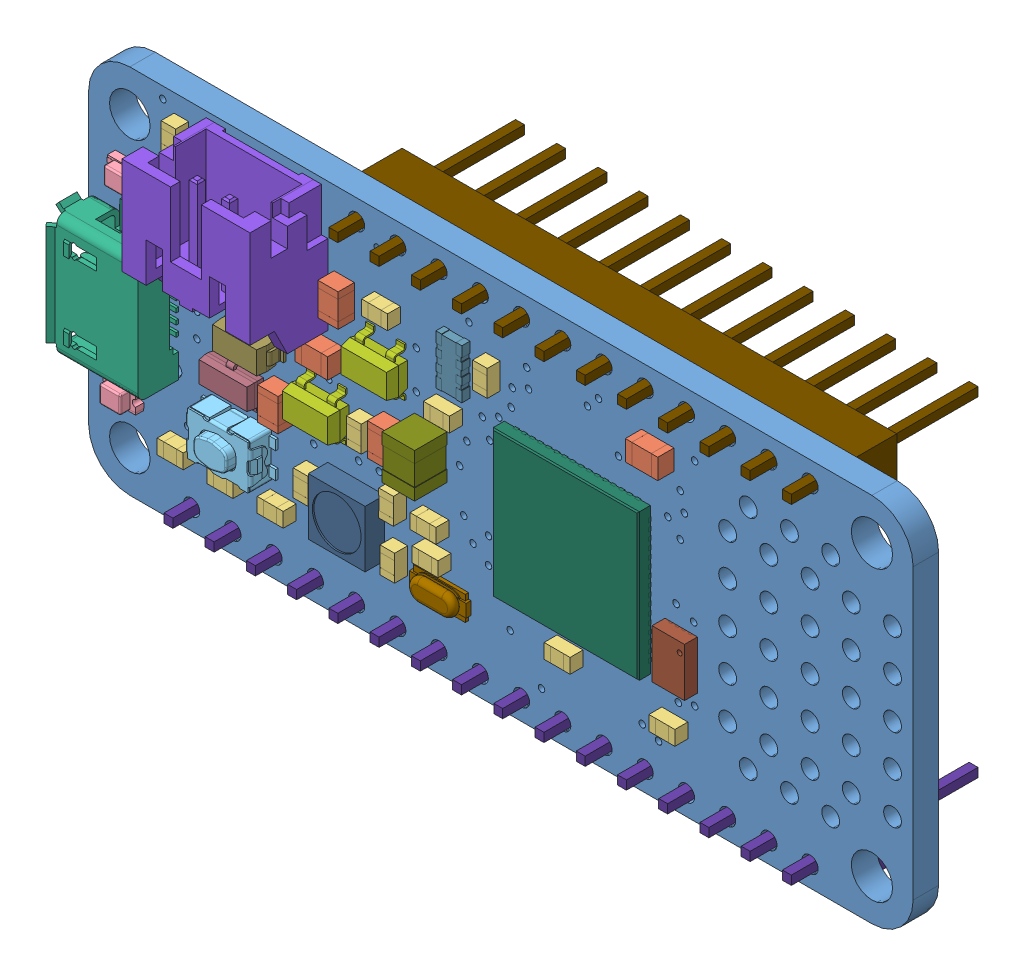
SolidWorks assembly 3857 Adafruit Feather M4 Express headers, configuration Default. Lengths in mm.
Overall size (50.85 22.86 14.87).
41 component instances, 18 part files, 6 mates.
Components (placement in the parent):
- 3857 Adafruit Feather M4 Express-1: 3857 Adafruit Feather M4 Express [Default] at origin size (50.85 22.86 6.37)
  - 3857 Adafruit Feather M4 Express(2)^3857 Adafruit Feather M4 Express-1: 3857 Adafruit Feather M4 Express(2)^3857 Adafruit Feather M4 Express [Default] at origin size (50.85 22.86 6.37) (virtual)
    - PCB Component^3857 Adafruit Feather M4 Express(2)_3857 Adafruit Feather M4 Express-1: PCB Component^3857 Adafruit Feather M4 Express(2)_3857 Adafruit Feather M4 Express [Default] at origin size (50.85 22.86 6.37) (virtual)
      - Board^PCB Component_3857 Adafruit Feather M4 Express(2)_3857 Adafruit Feather M4 Express-1: Board^PCB Component_3857 Adafruit Feather M4 Express(2)_3857 Adafruit Feather M4 Express [Default] at origin size (50.8 22.86 1.57) (virtual)
      - 10uF^PCB Component_3857 Adafruit Feather M4 Express(2)_3857 Adafruit Feather M4 Express-1: 10uF^PCB Component_3857 Adafruit Feather M4 Express(2)_3857 Adafruit Feather M4 Express [Default] at (12.042 9.838 1.57) x (0 -1 0) z (0 0 1) size (2 1.25 1) (virtual)
      - 10uF^PCB Component_3857 Adafruit Feather M4 Express(2)_3857 Adafruit Feather M4 Express-2: 10uF^PCB Component_3857 Adafruit Feather M4 Express(2)_3857 Adafruit Feather M4 Express [Default] at (14.728 13.858 1.57) size (2 1.25 1) (virtual)
      - 10uF^PCB Component_3857 Adafruit Feather M4 Express(2)_3857 Adafruit Feather M4 Express-3: 10uF^PCB Component_3857 Adafruit Feather M4 Express(2)_3857 Adafruit Feather M4 Express [Default] at (15.748 17.272 1.57) x (0 -1 0) z (0 0 1) size (2 1.25 1) (virtual)
      - 10uF^PCB Component_3857 Adafruit Feather M4 Express(2)_3857 Adafruit Feather M4 Express-4: 10uF^PCB Component_3857 Adafruit Feather M4 Express(2)_3857 Adafruit Feather M4 Express [Default] at (35.065 18.669 1.57) size (2 1.25 1) (virtual)
      - 10uF^PCB Component_3857 Adafruit Feather M4 Express(2)_3857 Adafruit Feather M4 Express-5: 10uF^PCB Component_3857 Adafruit Feather M4 Express(2)_3857 Adafruit Feather M4 Express [Default] at (18.796 11.303 1.57) x (0 -1 0) z (0 0 1) size (2 1.25 1) (virtual)
      - 1uF^PCB Component_3857 Adafruit Feather M4 Express(2)_3857 Adafruit Feather M4 Express-1: 1uF^PCB Component_3857 Adafruit Feather M4 Express(2)_3857 Adafruit Feather M4 Express [Default] at (24.909 17.78 1.57) x (0 1 0) z (0 0 1) size (1.6 0.9 0.8) (virtual)
      - 1uF^PCB Component_3857 Adafruit Feather M4 Express(2)_3857 Adafruit Feather M4 Express-2: 1uF^PCB Component_3857 Adafruit Feather M4 Express(2)_3857 Adafruit Feather M4 Express [Default] at (11.989 4.218 1.57) size (1.6 0.9 0.8) (virtual)
      - 1uF^PCB Component_3857 Adafruit Feather M4 Express(2)_3857 Adafruit Feather M4 Express-3: 1uF^PCB Component_3857 Adafruit Feather M4 Express(2)_3857 Adafruit Feather M4 Express [Default] at (5.715 20.955 1.57) x (0 -1 0) z (0 0 1) size (1.6 0.9 0.8) (virtual)
      - 1uF^PCB Component_3857 Adafruit Feather M4 Express(2)_3857 Adafruit Feather M4 Express-4: 1uF^PCB Component_3857 Adafruit Feather M4 Express(2)_3857 Adafruit Feather M4 Express [Default] at (5.829 4.254 1.57) size (1.6 0.9 0.8) (virtual)
      - 1uF^PCB Component_3857 Adafruit Feather M4 Express(2)_3857 Adafruit Feather M4 Express-5: 1uF^PCB Component_3857 Adafruit Feather M4 Express(2)_3857 Adafruit Feather M4 Express [Default] at (18.415 17.97 1.57) size (1.6 0.9 0.8) (virtual)
      - 1uF^PCB Component_3857 Adafruit Feather M4 Express(2)_3857 Adafruit Feather M4 Express-6: 1uF^PCB Component_3857 Adafruit Feather M4 Express(2)_3857 Adafruit Feather M4 Express [Default] at (19.202 5.067 1.57) x (0 1 0) z (0 0 1) size (1.6 0.9 0.8) (virtual)
      - 1uF^PCB Component_3857 Adafruit Feather M4 Express(2)_3857 Adafruit Feather M4 Express-7: 1uF^PCB Component_3857 Adafruit Feather M4 Express(2)_3857 Adafruit Feather M4 Express [Default] at (21.526 6.35 1.57) x (-1 0 0) z (0 0 1) size (1.6 0.9 0.8) (virtual)
      - 1uF^PCB Component_3857 Adafruit Feather M4 Express(2)_3857 Adafruit Feather M4 Express-8: 1uF^PCB Component_3857 Adafruit Feather M4 Express(2)_3857 Adafruit Feather M4 Express [Default] at (36.119 4.648 1.57) x (-1 0 0) z (0 0 1) size (1.6 0.9 0.8) (virtual)
      - 1uF^PCB Component_3857 Adafruit Feather M4 Express(2)_3857 Adafruit Feather M4 Express-9: 1uF^PCB Component_3857 Adafruit Feather M4 Express(2)_3857 Adafruit Feather M4 Express [Default] at (19.126 8.065 1.57) x (0 1 0) z (0 0 1) size (1.6 0.9 0.8) (virtual)
      - 1uF^PCB Component_3857 Adafruit Feather M4 Express(2)_3857 Adafruit Feather M4 Express-10: 1uF^PCB Component_3857 Adafruit Feather M4 Express(2)_3857 Adafruit Feather M4 Express [Default] at (29.662 5.263 1.57) x (-1 0 0) z (0 0 1) size (1.6 0.9 0.8) (virtual)
      - 1uF^PCB Component_3857 Adafruit Feather M4 Express(2)_3857 Adafruit Feather M4 Express-11: 1uF^PCB Component_3857 Adafruit Feather M4 Express(2)_3857 Adafruit Feather M4 Express [Default] at (8.89 4.254 1.57) x (-1 0 0) z (0 0 1) size (1.6 0.9 0.8) (virtual)
      - 1uF^PCB Component_3857 Adafruit Feather M4 Express(2)_3857 Adafruit Feather M4 Express-12: 1uF^PCB Component_3857 Adafruit Feather M4 Express(2)_3857 Adafruit Feather M4 Express [Default] at (17.145 10.922 1.57) x (0 1 0) z (0 0 1) size (1.6 0.9 0.8) (virtual)
      - 1uF^PCB Component_3857 Adafruit Feather M4 Express(2)_3857 Adafruit Feather M4 Express-13: 1uF^PCB Component_3857 Adafruit Feather M4 Express(2)_3857 Adafruit Feather M4 Express [Default] at (13.856 6.502 1.57) x (0 -1 0) z (0 0 1) size (1.6 0.9 0.8) (virtual)
      - 1uF^PCB Component_3857 Adafruit Feather M4 Express(2)_3857 Adafruit Feather M4 Express-14: 1uF^PCB Component_3857 Adafruit Feather M4 Express(2)_3857 Adafruit Feather M4 Express [Default] at (21.4 8.065 1.57) size (1.6 0.9 0.8) (virtual)
      - 1uF^PCB Component_3857 Adafruit Feather M4 Express(2)_3857 Adafruit Feather M4 Express-15: 1uF^PCB Component_3857 Adafruit Feather M4 Express(2)_3857 Adafruit Feather M4 Express [Default] at (22.225 14.414 1.57) x (-1 0 0) z (0 0 1) size (1.6 0.9 0.8) (virtual)
      - ORANGE^PCB Component_3857 Adafruit Feather M4 Express(2)_3857 Adafruit Feather M4 Express-1: ORANGE^PCB Component_3857 Adafruit Feather M4 Express(2)_3857 Adafruit Feather M4 Express [Default] at (2.645 17.359 1.57) x (0 1 0) z (0 0 1) size (1.25 2.02 1.1) (virtual)
      - ORANGE^PCB Component_3857 Adafruit Feather M4 Express(2)_3857 Adafruit Feather M4 Express-2: ORANGE^PCB Component_3857 Adafruit Feather M4 Express(2)_3857 Adafruit Feather M4 Express [Default] at (2.413 5.588 1.57) x (0 -1 0) z (0 0 1) size (1.25 2.02 1.1) (virtual)
      - KMR2^PCB Component_3857 Adafruit Feather M4 Express(2)_3857 Adafruit Feather M4 Express-1: KMR2^PCB Component_3857 Adafruit Feather M4 Express(2)_3857 Adafruit Feather M4 Express [Default] at (9.398 6.54 1.57) x (-1 0 0) z (0 0 1) size (4.6 2.8 1.94) (virtual)
      - microUSB^PCB Component_3857 Adafruit Feather M4 Express(2)_3857 Adafruit Feather M4 Express-1: microUSB^PCB Component_3857 Adafruit Feather M4 Express(2)_3857 Adafruit Feather M4 Express [Default] at (4.445 11.43 1.57) x (0 -1 0) z (0 0 1) size (8.8 5.6 3) (virtual)
      - MCP73831T-2ACI_OT^PCB Component_3857 Adafruit Feather M4 Express(2)_3857 Adafruit Feather M4 Express-1: MCP73831T-2ACI_OT^PCB Component_3857 Adafruit Feather M4 Express(2)_3857 Adafruit Feather M4 Express [Default] at (14.732 10.922 1.57) size (3 3 1.4) (virtual)
      - MCP73831T-2ACI_OT^PCB Component_3857 Adafruit Feather M4 Express(2)_3857 Adafruit Feather M4 Express-2: MCP73831T-2ACI_OT^PCB Component_3857 Adafruit Feather M4 Express(2)_3857 Adafruit Feather M4 Express [Default] at (18.352 15.113 1.57) size (3 3 1.4) (virtual)
      - JSTPH^PCB Component_3857 Adafruit Feather M4 Express(2)_3857 Adafruit Feather M4 Express-1: JSTPH^PCB Component_3857 Adafruit Feather M4 Express(2)_3857 Adafruit Feather M4 Express [Default] at (10.795 19.304 1.57) size (7.9 8.6 4.8) (virtual)
      - 32.768^PCB Component_3857 Adafruit Feather M4 Express(2)_3857 Adafruit Feather M4 Express-1: 32.768^PCB Component_3857 Adafruit Feather M4 Express(2)_3857 Adafruit Feather M4 Express [Default] at (21.806 4.496 1.57) x (-1 0 0) z (0 0 1) size (3.5 1.5 0.8) (virtual)
      - WS2812B3535^PCB Component_3857 Adafruit Feather M4 Express(2)_3857 Adafruit Feather M4 Express-1: WS2812B3535^PCB Component_3857 Adafruit Feather M4 Express(2)_3857 Adafruit Feather M4 Express [Default] at (16.485 6.109 1.57) x (0 -1 0) z (0 0 1) size (3.5 3.5 1.2) (virtual)
      - 2MB Flash^PCB Component_3857 Adafruit Feather M4 Express(2)_3857 Adafruit Feather M4 Express-1: 2MB Flash^PCB Component_3857 Adafruit Feather M4 Express(2)_3857 Adafruit Feather M4 Express [Default] at (36.512 8.433 1.57) x (0 1 0) z (0 0 1) size (3 2 0.8) (virtual)
      - MBR120^PCB Component_3857 Adafruit Feather M4 Express(2)_3857 Adafruit Feather M4 Express-1: MBR120^PCB Component_3857 Adafruit Feather M4 Express(2)_3857 Adafruit Feather M4 Express [Default] at (10.35 12.319 1.57) x (-1 0 0) z (0 0 1) size (3.6 1.4 1.35) (virtual)
      - DMG341^PCB Component_3857 Adafruit Feather M4 Express(2)_3857 Adafruit Feather M4 Express-1: DMG341^PCB Component_3857 Adafruit Feather M4 Express(2)_3857 Adafruit Feather M4 Express [Default] at (9.398 9.842 1.57) size (3.04 2.64 1.12) (virtual)
      - 100K^PCB Component_3857 Adafruit Feather M4 Express(2)_3857 Adafruit Feather M4 Express-1: 100K^PCB Component_3857 Adafruit Feather M4 Express(2)_3857 Adafruit Feather M4 Express [Default] at (22.67 17.208 1.57) x (0 1 0) z (0 0 1) size (3.05 1.6 0.5) (virtual)
      - ATSAMD51J^PCB Component_3857 Adafruit Feather M4 Express(2)_3857 Adafruit Feather M4 Express-1: ATSAMD51J^PCB Component_3857 Adafruit Feather M4 Express(2)_3857 Adafruit Feather M4 Express [Default] at (30.162 11.049 1.57) x (0 1 0) z (0 0 1) size (9 9 0.8) (virtual)
      - 10uH^PCB Component_3857 Adafruit Feather M4 Express(2)_3857 Adafruit Feather M4 Express-1: 10uH^PCB Component_3857 Adafruit Feather M4 Express(2)_3857 Adafruit Feather M4 Express [Default] at (21.082 11.811 1.57) x (0 -1 0) z (0 0 1) size (2.7 2 2) (virtual)
- header_m16-1: header_m16 [Default] at (5.08 1.27 -2.5) x (1 0 0) z (0 -1 0) size (40.64 11.5 2.5)
- header_m12-1: header_m12 [Default] at (15.24 21.59 -2.5) x (1 0 0) z (0 -1 0) size (30.48 11.5 2.5)
Mates (geometry in assembly coordinates):
- Concentric1: concentric anti-aligned: line of header_m12-1 through (16.51 21.59 -2.5) axis (0 0 -1); cylinder of 3857 Adafruit Feather M4 Express-1/3857 Adafruit Feather M4 Express(2)^3857 Adafruit Feather M4 Express-1/PCB Component^3857 Adafruit Feather M4 Express(2)_3857 Adafruit Feather M4 Express-1/Board^PCB Component_3857 Adafruit Feather M4 Express(2)_3857 Adafruit Feather M4 Express-1 through (16.51 21.59 0) axis (0 0 1) radius 0.5
- Concentric3: concentric anti-aligned: cylinder of 3857 Adafruit Feather M4 Express-1/3857 Adafruit Feather M4 Express(2)^3857 Adafruit Feather M4 Express-1/PCB Component^3857 Adafruit Feather M4 Express(2)_3857 Adafruit Feather M4 Express-1/Board^PCB Component_3857 Adafruit Feather M4 Express(2)_3857 Adafruit Feather M4 Express-1 through (44.45 21.59 0) axis (0 0 1) radius 0.5; line of header_m12-1 through (44.45 21.59 -2.5) axis (0 0 -1)
- Coincident1: coincident anti-aligned: plane of 3857 Adafruit Feather M4 Express-1/3857 Adafruit Feather M4 Express(2)^3857 Adafruit Feather M4 Express-1/PCB Component^3857 Adafruit Feather M4 Express(2)_3857 Adafruit Feather M4 Express-1/Board^PCB Component_3857 Adafruit Feather M4 Express(2)_3857 Adafruit Feather M4 Express-1 through (25.4 11.43 0) normal (0 0 -1); plane of header_m12-1 through (15.24 20.34 0) normal (0 0 1)
- Concentric4: concentric anti-aligned: cylinder of 3857 Adafruit Feather M4 Express-1/3857 Adafruit Feather M4 Express(2)^3857 Adafruit Feather M4 Express-1/PCB Component^3857 Adafruit Feather M4 Express(2)_3857 Adafruit Feather M4 Express-1/Board^PCB Component_3857 Adafruit Feather M4 Express(2)_3857 Adafruit Feather M4 Express-1 through (6.35 1.27 0) axis (0 0 1) radius 0.5; line of header_m16-1 through (6.35 1.27 -2.5) axis (0 0 -1)
- Concentric6: concentric anti-aligned: cylinder of 3857 Adafruit Feather M4 Express-1/3857 Adafruit Feather M4 Express(2)^3857 Adafruit Feather M4 Express-1/PCB Component^3857 Adafruit Feather M4 Express(2)_3857 Adafruit Feather M4 Express-1/Board^PCB Component_3857 Adafruit Feather M4 Express(2)_3857 Adafruit Feather M4 Express-1 through (44.45 1.27 0) axis (0 0 1) radius 0.5; line of header_m16-1 through (44.45 1.27 -2.5) axis (0 0 -1)
- Coincident4: coincident anti-aligned: plane of 3857 Adafruit Feather M4 Express-1/3857 Adafruit Feather M4 Express(2)^3857 Adafruit Feather M4 Express-1/PCB Component^3857 Adafruit Feather M4 Express(2)_3857 Adafruit Feather M4 Express-1/Board^PCB Component_3857 Adafruit Feather M4 Express(2)_3857 Adafruit Feather M4 Express-1 through (25.4 11.43 0) normal (0 0 -1); plane of header_m16-1 through (5.08 0.02 0) normal (0 0 1)
